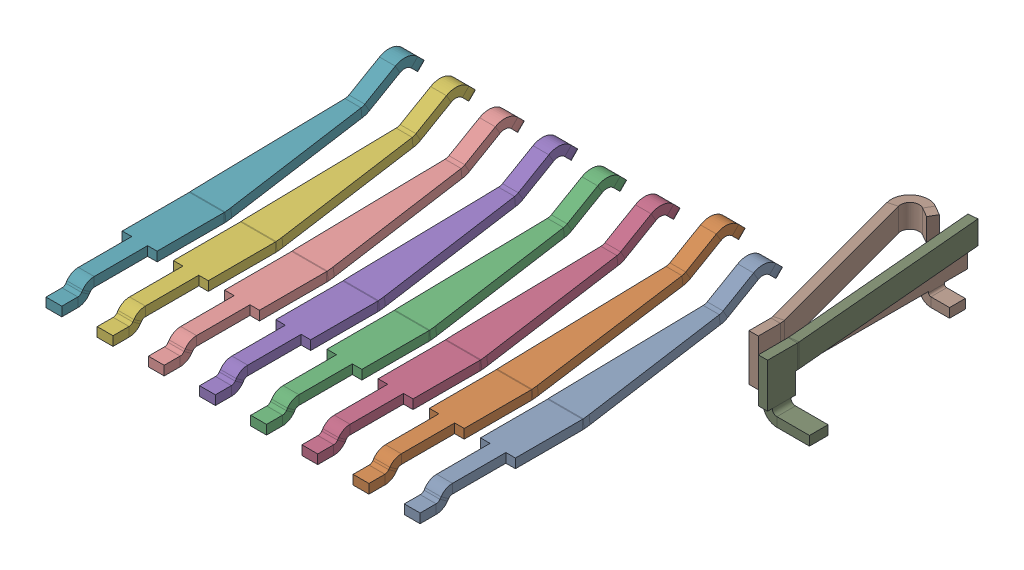
SolidWorks assembly leads.stp, configuration Default. Lengths in mm.
Overall size (10.97 1.32 10.44).
10 component instances, 5 part files, 0 mates.
Components (placement in the parent):
- Component12.stp-1: Component12.stp [Default] at origin size (0.75 1.14 7.86)
- Component13.stp-1: Component13.stp [Default] at (-1.1 0 0) size (0.75 1.16 8.16)
- Component14.stp-1: Component14.stp [Default] at (-3.3 0 0) size (0.75 1.13 7.81)
- Component12.stp-2: Component12.stp [Default] at (-2.2 0 0) size (0.75 1.14 7.86)
- Component12.stp-3: Component12.stp [Default] at (-4.4 0 0) size (0.75 1.14 7.86)
- Component12.stp-4: Component12.stp [Default] at (-6.6 0 0) size (0.75 1.14 7.86)
- Component12.stp-5: Component12.stp [Default] at (-7.7 0 0) size (0.75 1.14 7.86)
- Component15.stp-1: Component15.stp [Default] at origin size (1.57 1.27 4.5)
- Component16.stp-1: Component16.stp [Default] at origin size (1.37 1.25 4.89)
- Component14.stp-2: Component14.stp [Default] at (-5.5 0 0) size (0.75 1.13 7.81)
